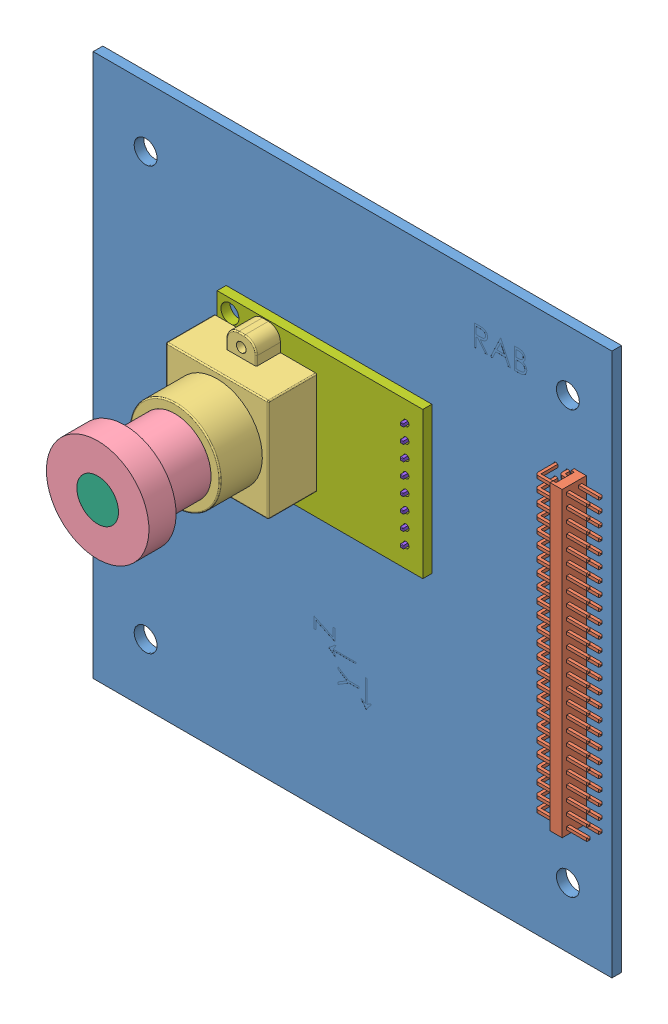
SolidWorks assembly B3_mission_board, configuration ﾃﾞﾌｫﾙﾄ. Lengths in mm.
Overall size (86 90 33.7).
9 component instances, 8 part files, 6 mates.
Components (placement in the parent):
- B3_internal_board_mission-1: B3_internal_board_mission [ﾃﾞﾌｫﾙﾄ] at (39.4484 44.7592 89.2) size (86 90 1.6)
- B3_50pinL-1: B3_50pinL [Default] at (33.1984 24.7592 90.8) x (0 -1 0) z (0 0 1) size (50 8.75 7)
- ArduCam-1: ArduCam [ﾃﾞﾌｫﾙﾄ] at (-14.3682 35.4592 102.4386) x (1 0 0) z (0 -1 0) size (37.49 33.7 24.3)
  - ArduCam1-1: ArduCam1 [ﾃﾞﾌｫﾙﾄ] at (-0.7335 -8.7389 24) size (17 15 24)
  - ArduCam2-1: ArduCam2 [ﾃﾞﾌｫﾙﾄ] at (-0.7335 6.2611 24) x (-0.444964 0 -0.895549) z (0.895549 0 -0.444964) size (17 12.8 17)
  - ArduCam3-1: ArduCam3 [ﾃﾞﾌｫﾙﾄ] at (-0.7335 15.4611 24) x (0.979645 0 0.200737) z (-0.200737 0 0.979645) size (4.5 2.25 4.5)
  - ArduCam4-1: ArduCam4 [ﾃﾞﾌｫﾙﾄ] at (-0.7335 19.0611 24) x (0.837169 0 0.546944) z (0.546944 0 -0.837169) size (6.9 0.2 6.9)
  - ArduCam_Board-1: ArduCam_Board [ﾃﾞﾌｫﾙﾄ] at (8.3165 -10.2389 24) x (0 0 -1) z (1 0 0) size (24.3 1.5 34.1)
  - ArduCam_pin-1: ArduCam_pin [Default] at (21.3665 -10.2389 34.05) size (2 6.4 20)
Mates (geometry in assembly coordinates):
- Coincident1: coincident anti-aligned: plane of B3_internal_board_mission-1 through (39.4484 44.7592 90.8) normal (0 0 1); plane of B3_50pinL-1 through (35.1984 24.7592 90.8) normal (0 0 -1)
- Distance1: distance = 20 mm aligned: plane of B3_50pinL-1 through (35.1984 24.7592 90.8) normal (0 1 0); plane of B3_internal_board_mission-1 through (39.4484 44.7592 90.8) normal (0 1 0)
- Distance2: distance = 6.25 mm anti-aligned: plane of B3_50pinL-1 through (33.1984 24.7592 90.8) normal (-1 0 0); plane of B3_internal_board_mission-1 through (39.4484 -45.2408 90.8) normal (1 0 0)
- Coincident2: coincident anti-aligned: plane of B3_internal_board_mission-1 through (39.4484 44.7592 90.8) normal (0 0 1); plane of ArduCam-1/ArduCam_pin-1 through (7.0984 21.4092 90.8) normal (0 0 -1)
- Distance3: distance = 21.15 mm aligned: plane of ArduCam-1/ArduCam_Board-1 through (-23.1016 23.6092 93.6997) normal (0 1 0); plane of B3_internal_board_mission-1 through (39.4484 44.7592 90.8) normal (0 1 0)
- Distance5: distance = 28.45 mm aligned: plane of ArduCam-1/ArduCam_Board-1 through (10.9984 -0.6908 93.6997) normal (1 0 0); plane of B3_internal_board_mission-1 through (39.4484 -45.2408 90.8) normal (1 0 0)
